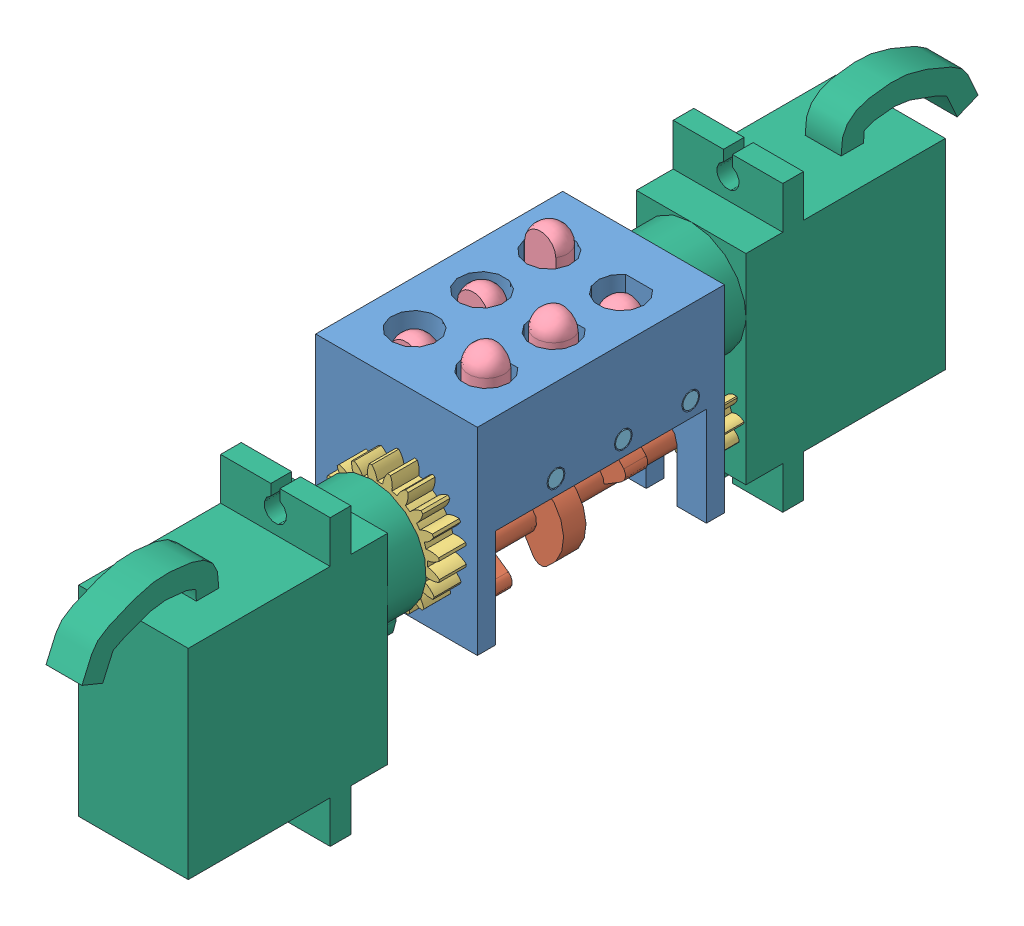
SolidWorks assembly cell, configuration По умолчанию. Lengths in mm.
Overall size (20.18 34.4 106.77).
23 component instances, 6 part files, 37 mates.
Components (placement in the parent):
- housing-1: housing [По умолчанию] at origin size (18 22 27.5)
- rotor-1: rotor [По умолчанию] at (4 -16 -17.35) x (0.358478 -0.933538 0) z (0 0 1) size (9 8.9 33.5)
  - rotor-1: rotor [По умолчанию] at origin size (9 8.9 33.5)
  - spur gear_am-1: spur gear_am [Metric - Spur gear 0.6M 10T 20PA 3FW ---S10N75H50L3N] at (0 0 3) x (0 0 -1) z (1 0 0) size (3 6.89 7.2)
- pin-2: pin [По умолчанию] at (4 -9.7016 -0.75) x (-1 0 0) z (0 0 -1) size (4 14 4.5)
- pin-3: pin [По умолчанию] at (4 -12.4261 -8.25) x (-1 0 0) z (0 0 -1) size (4 14 4.5)
- separator-1: separator [По умолчанию] at (0 -9.3 5) size (9 1.75 1.75)
- separator-2: separator [По умолчанию] at (0 -9.3 -2.5) size (9 1.75 1.75)
- rotor-3: rotor [По умолчанию] at (-4 -16 18.952) x (0.331867 0.943326 0) z (0 0 -1) size (9 8.9 33.5)
  - rotor-1: rotor [По умолчанию] at origin size (9 8.9 33.5)
  - spur gear_am-1: spur gear_am [Metric - Spur gear 0.6M 10T 20PA 3FW ---S10N75H50L3N] at (0 0 3) x (0 0 -1) z (1 0 0) size (3 6.89 7.2)
- pin-4: pin [По умолчанию] at (4 -9.3768 6.75) x (-1 0 0) z (0 0 -1) size (4 14 4.5)
- separator-3: separator [По умолчанию] at (0 -9.3 -10) size (9 1.75 1.75)
- servo-1: servo [По умолчанию] at (-3.6042 -4.7 -44.85) x (-1 0 0) z (0 1 0) size (12.2 36.83 31.7)
- servo-2: servo [По умолчанию] at (3.4181 -4.7 46.452) x (1 0 0) z (0 1 0) size (12.2 36.83 31.7)
- spur gear_am-1: spur gear_am [Metric - Spur gear 0.6M 20T 20PA 3FW ---S20N75H50L5N] at (3.4181 -10.8 15.952) x (0 0 1) z (-0.999929 -0.011884 0) size (3 13.08 13.08)
- spur gear_am-2: spur gear_am [Metric - Spur gear 0.6M 20T 20PA 3FW ---S20N75H50L5N] at (-3.6042 -10.8 -14.35) x (0 0 -1) z (1 0 0) size (3 13.08 13.08)
- separator-4: separator [По умолчанию] at (-9 -9.3 -5) size (9 1.75 1.75)
- separator-5: separator [По умолчанию] at (-9 -9.3 2.5) size (9 1.75 1.75)
- separator-6: separator [По умолчанию] at (-9 -9.3 10) size (9 1.75 1.75)
- pin-5: pin [По умолчанию] at (-4 -9.2986 -6.25) size (4 14 4.5)
- pin-6: pin [По умолчанию] at (-4 -11.4111 1.25) size (4 14 4.5)
- pin-7: pin [По умолчанию] at (-4 -12.4437 8.75) size (4 14 4.5)
Mates (geometry in assembly coordinates):
- Концентричный1: concentric anti-aligned: cylinder of housing-1 through (4 -16 11.75) axis (0 0 1) radius 1.7; cylinder of rotor-1/rotor-1 through (4 -16 16.15) axis (0 0 -1) radius 1.5
- Расстояние1: distance = 0.1 mm anti-aligned: plane of rotor-1/rotor-1 through (4 -16 11.65) normal (0 0 1); plane of housing-1 through (0 0 11.75) normal (0 0 -1)
- Концентричный2: concentric anti-aligned: cylinder of housing-1 through (4 -1.5 7.25) axis (0 1 0) radius 2.5; cylinder of ? through (4 0.5361 7.25) axis (0 -1 0) radius 2
- Параллельность1: parallel aligned: plane of housing-1 through (9 -2.5 -13.75) normal (1 0 0); plane of ? through (6 -9.4639 10.75) normal (1 0 0)
- Концентричный3: concentric anti-aligned: cylinder of housing-1 through (4 -3.5 0.25) axis (0 1 0) radius 2.5; cylinder of pin-2 through (4 0.2984 0.25) axis (0 -1 0) radius 2
- Концентричный4: concentric anti-aligned: cylinder of housing-1 through (4 -3.5 -7.25) axis (0 1 0) radius 2.5; cylinder of pin-3 through (4 -2.4261 -7.25) axis (0 -1 0) radius 2
- Параллельность2: parallel aligned: plane of housing-1 through (-5.7 0 11.75) normal (1 0 0); plane of pin-2 through (6 -9.7016 3.75) normal (1 0 0)
- Параллельность3: parallel aligned: plane of housing-1 through (-5.7 0 11.75) normal (1 0 0); plane of pin-3 through (6 -12.4261 -3.75) normal (1 0 0)
- Концентричный5: concentric anti-aligned: cylinder of housing-1 through (0 -9.3 5) axis (1 0 0) radius 1; cylinder of separator-1 through (9 -9.3 5) axis (-1 0 0) radius 0.875
- Совпадение5: coincident aligned: plane of housing-1 through (9 -3.5 -13.75) normal (1 0 0); plane of separator-1 through (9 -9.3 5) normal (1 0 0)
- Совпадение6: coincident aligned: plane of housing-1 through (9 -3.5 -13.75) normal (1 0 0); plane of separator-2 through (9 -9.3 -2.5) normal (1 0 0)
- Концентричный7: concentric anti-aligned: cylinder of housing-1 through (-4 -16 -11.75) axis (0 0 -1) radius 1.7; cylinder of rotor-3/rotor-1 through (-4 -16 -14.548) axis (0 0 1) radius 1.5
- Концентричный8: concentric anti-aligned: cylinder of housing-1 through (4 -3.5 7.75) axis (0 1 0) radius 2.5; cylinder of pin-4 through (4 0.6232 7.75) axis (0 -1 0) radius 2
- Параллельность4: parallel anti-aligned: plane of housing-1 through (2.5 -3.5 5.75) normal (0 0 1); plane of pin-4 through (4 -9.3768 6.75) normal (0 0 -1)
- Концентричный9: concentric anti-aligned: cylinder of housing-1 through (0 -9.3 -2.5) axis (1 0 0) radius 1; cylinder of separator-2 through (9 -9.3 -2.5) axis (-1 0 0) radius 0.875
- Совпадение8: coincident aligned: plane of housing-1 through (9 -3.5 -13.75) normal (1 0 0); plane of separator-3 through (9 -9.3 -10) normal (1 0 0)
- Концентричный10: concentric anti-aligned: cylinder of housing-1 through (0 -9.3 -10) axis (1 0 0) radius 1; cylinder of separator-3 through (9 -9.3 -10) axis (-1 0 0) radius 0.875
- Концентричный11: concentric anti-aligned: cylinder of servo-2 through (3.4181 -10.8 17.352) axis (0 0 1) radius 2.5; cylinder of spur gear_am-1 through (3.4181 -10.8 65.9521) axis (0 0 -1) radius 2.5
- Расстояние2: distance = 1 mm anti-aligned: plane of spur gear_am-1 through (3.4181 -10.8 18.952) normal (0 0 1); plane of servo-2 through (3.4181 -16.9 19.952) normal (0 0 -1)
- Расстояние3: distance = 1 mm anti-aligned: plane of spur gear_am-2 through (-3.6042 -10.8 -17.35) normal (0 0 -1); plane of servo-1 through (-3.6042 -16.9 -18.35) normal (0 0 1)
- Концентричный12: concentric anti-aligned: cylinder of servo-1 through (-3.6042 -10.8 -15.75) axis (0 0 -1) radius 2.5; cylinder of spur gear_am-2 through (-3.6042 -10.8 -64.3501) axis (0 0 1) radius 2.5
- Совпадение14: coincident aligned: plane of rotor-3/spur gear_am-1 through (-4 -16 15.952) normal (0 0 -1); plane of spur gear_am-1 through (3.4181 -10.8 15.952) normal (0 0 -1)
- Совпадение15: coincident aligned: plane of rotor-1/spur gear_am-1 through (4 -16 -14.35) normal (0 0 1); plane of spur gear_am-2 through (-3.6042 -10.8 -14.35) normal (0 0 1)
- Совпадение16: coincident aligned: plane of servo-1 through (-9.7042 -27 -44.85) normal (0 -1 0); plane of servo-2 through (9.5181 -27 46.452) normal (0 -1 0)
- Совпадение17: coincident aligned: plane of housing-1 through (0 0 0) normal (0 1 0); plane of servo-2 through (9.5181 0 28.352) normal (0 1 0)
- Концентричный13: concentric aligned: cylinder of housing-1 through (0 -9.3 -5) axis (-1 0 0) radius 1; cylinder of separator-4 through (0 -9.3 -5) axis (-1 0 0) radius 0.875
- Совпадение18: coincident aligned: plane of housing-1 through (-9 -3.5 -13.75) normal (-1 0 0); plane of separator-4 through (-9 -9.3 -5) normal (-1 0 0)
- Концентричный14: concentric aligned: cylinder of housing-1 through (0 -9.3 2.5) axis (-1 0 0) radius 1; cylinder of separator-5 through (0 -9.3 2.5) axis (-1 0 0) radius 0.875
- Совпадение19: coincident aligned: plane of housing-1 through (-9 -3.5 -13.75) normal (-1 0 0); plane of separator-5 through (-9 -9.3 2.5) normal (-1 0 0)
- Концентричный15: concentric aligned: cylinder of housing-1 through (0 -9.3 10) axis (-1 0 0) radius 1; cylinder of separator-6 through (0 -9.3 10) axis (-1 0 0) radius 0.875
- Совпадение20: coincident aligned: plane of housing-1 through (-9 -3.5 -13.75) normal (-1 0 0); plane of separator-6 through (-9 -9.3 10) normal (-1 0 0)
- Концентричный16: concentric anti-aligned: cylinder of housing-1 through (-4 -3.5 -7.25) axis (0 1 0) radius 2.5; cylinder of pin-5 through (-4 0.7014 -7.25) axis (0 -1 0) radius 2
- Концентричный17: concentric anti-aligned: cylinder of housing-1 through (-4 -3.5 0.25) axis (0 1 0) radius 2.5; cylinder of pin-6 through (-4 -1.4111 0.25) axis (0 -1 0) radius 2
- Концентричный18: concentric anti-aligned: cylinder of housing-1 through (-4 -3.5 7.75) axis (0 1 0) radius 2.5; cylinder of pin-7 through (-4 -2.4437 7.75) axis (0 -1 0) radius 2
- Параллельность5: parallel aligned: plane of housing-1 through (-9 -3.5 13.75) normal (0 0 1); plane of pin-5 through (-4 -9.2986 -6.25) normal (0 0 1)
- Параллельность6: parallel aligned: plane of housing-1 through (-9 -3.5 13.75) normal (0 0 1); plane of pin-6 through (-4 -11.4111 1.25) normal (0 0 1)
- Параллельность7: parallel aligned: plane of housing-1 through (-9 -3.5 13.75) normal (0 0 1); plane of pin-7 through (-4 -12.4437 8.75) normal (0 0 1)
